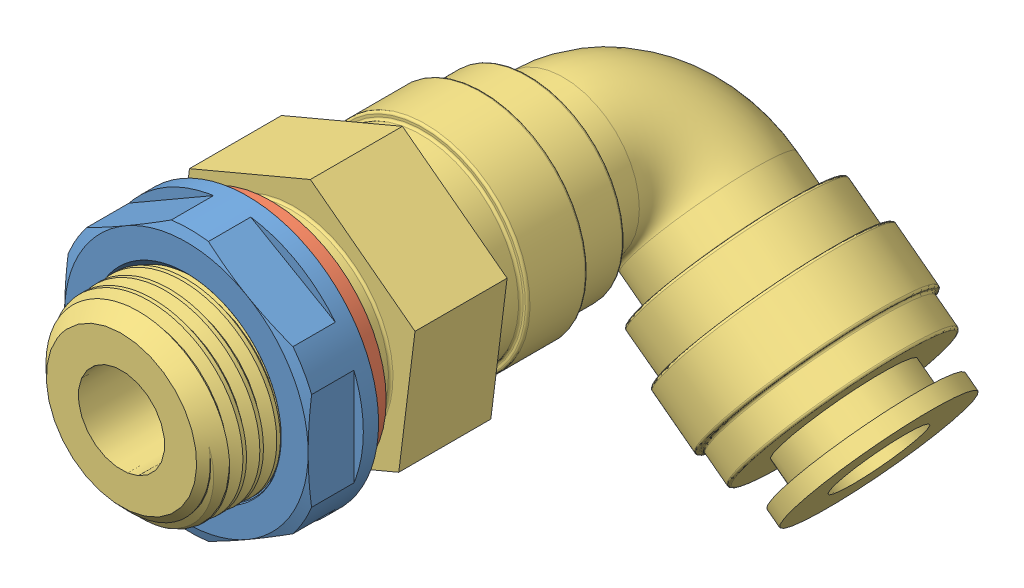
SolidWorks assembly 90_assembly, configuration Default. Lengths in mm.
Overall size (52.61 48.36 69.22).
3 component instances, 3 part files, 4 mates.
Components (placement in the parent):
- true_npt_nut-1: true_npt_nut [3185K112] at (-3.8428 13.2999 -10.4025) size (28.95 28.95 10.31)
- hrd-050-gasket-1: hrd-050-gasket [Default] at (-3.8428 13.2999 -13.0187) x (0.930255 -0.366913 0) z (-0.366913 -0.930255 0) size (25.4 2.62 25.4)
- through-wall-90-1: through-wall-90 [Default] at (-3.8428 13.2999 -15.5587) x (-0.797473 0.603354 0) z (-0.603354 -0.797473 0) size (46.99 69.22 25.08)
Mates (geometry in assembly coordinates):
- Coincident1: coincident anti-aligned: plane of true_npt_nut-1 through (-3.8428 28.8152 -10.4025) normal (0 0 -1); plane of hrd-050-gasket-1 through (-3.8428 13.2999 -10.4025) normal (0 0 1)
- Concentric1: concentric aligned: circle of true_npt_nut-1; circle of hrd-050-gasket-1
- Distance1: distance = 2.54 mm anti-aligned: plane of through-wall-90-1 through (-3.8428 13.2999 -15.5587) normal (0 0 1); plane of hrd-050-gasket-1 through (-3.8428 13.2999 -13.0187) normal (0 0 -1)
- Concentric2: concentric anti-aligned: circle of hrd-050-gasket-1; circle of through-wall-90-1
